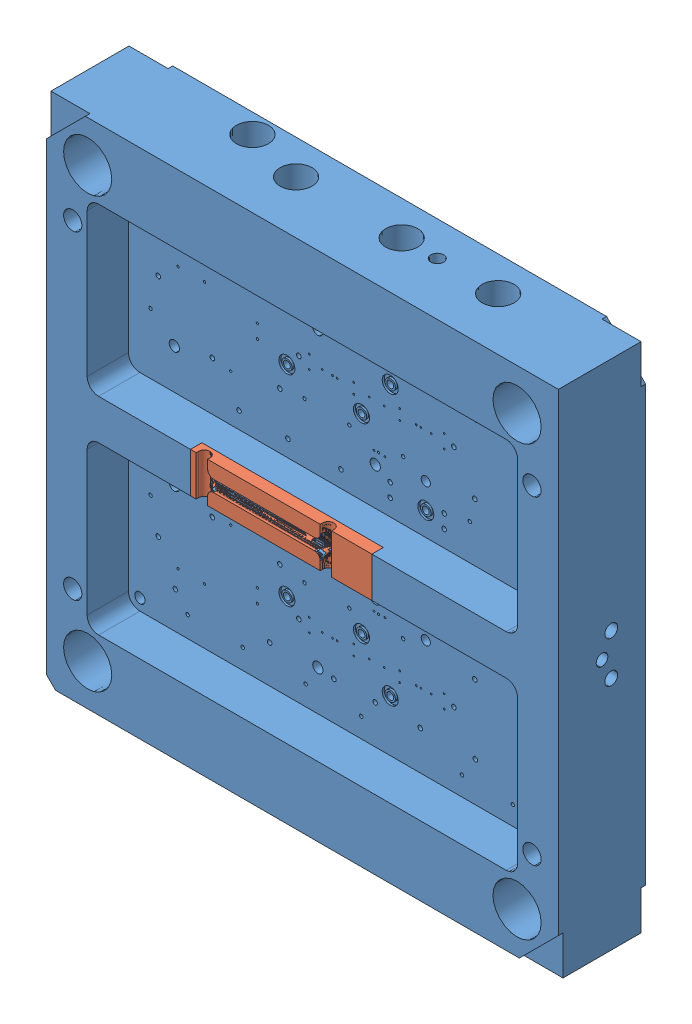
SolidWorks assembly Sestava1, configuration Výchozí. Lengths in mm.
Overall size (446 446 76).
2 component instances, 2 part files, 4 mates.
Components (placement in the parent):
- 160031-03A-1: 160031-03A [Výchozí] at origin size (446 446 76)
- VLOŽKA-1: VLOŽKA [Výchozí] at origin size (158 35 10)
Mates (geometry in assembly coordinates):
- Namístě1: in place: plane of ? through (0 0 0) normal (0 0 1); moOrthogonalPlaneRef_w of ? through (0 0 0) normal (0 1 0); plane of ? through (0 0 0) normal (1 0 0); unknown of ?
- Sjednocená1: coincident aligned: plane of VLOŽKA-1; plane of assembly
- Sjednocená2: coincident aligned: plane of ? through (0 0 0) normal (0 1 0)
- Sjednocená3: coincident anti-aligned: plane of ? through (0 0 0) normal (1 0 0)
